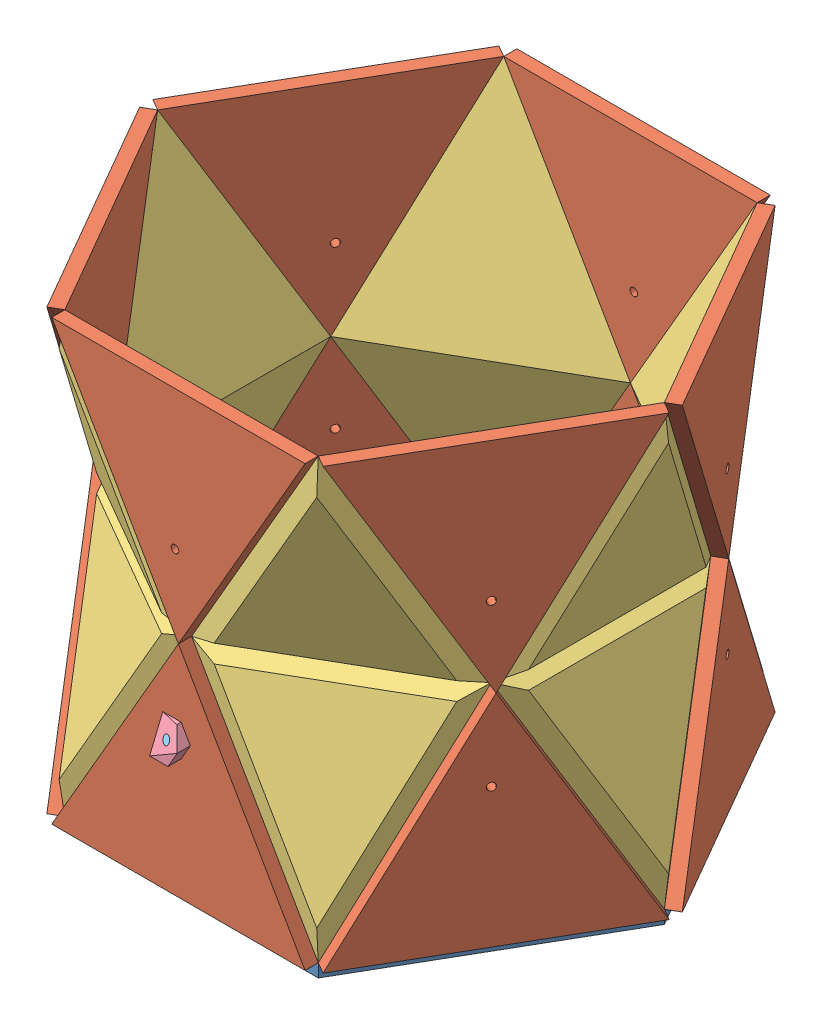
SolidWorks assembly rockPot, configuration Default. Lengths in mm.
Overall size (131.34 103 125.83).
31 component instances, 6 part files, 3 mates.
Components (placement in the parent):
- base^rockPot-2: base^rockPot [Default] at origin size (115.47 3 100) (virtual)
- ring^rockPot-2: ring^rockPot [Default] at origin size (131.34 50 125.83) (virtual)
  - template^ring_rockPot-1: template^ring_rockPot [Default] at (0 3 0) x (1 0 0) z (0 1 0) size (115.47 100 0) (virtual)
  - triA^ring_rockPot-1: triA^ring_rockPot [Default] at (0 0 50) size (57.74 50 3) (virtual)
  - triB^ring_rockPot-1: triB^ring_rockPot [Default] at origin size (43.3 50 25.83) (virtual)
  - triA^ring_rockPot-2: triA^ring_rockPot [Default] at (43.3013 0 25) x (0.5 0 -0.866025) z (0.866025 0 0.5) size (57.74 50 3) (virtual)
  - triA^ring_rockPot-3: triA^ring_rockPot [Default] at (43.3013 0 -25) x (-0.5 0 -0.866025) z (0.866025 0 -0.5) size (57.74 50 3) (virtual)
  - triA^ring_rockPot-4: triA^ring_rockPot [Default] at (0 0 -50) x (-1 0 0) z (0 0 -1) size (57.74 50 3) (virtual)
  - triA^ring_rockPot-5: triA^ring_rockPot [Default] at (-43.3013 0 -25) x (-0.5 0 0.866025) z (-0.866025 0 -0.5) size (57.74 50 3) (virtual)
  - triA^ring_rockPot-6: triA^ring_rockPot [Default] at (-43.3013 0 25) x (0.5 0 0.866025) z (-0.866025 0 0.5) size (57.74 50 3) (virtual)
  - triB^ring_rockPot-2: triB^ring_rockPot [Default] x (0.5 0 -0.866025) z (0.866025 0 0.5) size (43.3 50 25.83) (virtual)
  - triB^ring_rockPot-3: triB^ring_rockPot [Default] x (-0.5 0 -0.866025) z (0.866025 0 -0.5) size (43.3 50 25.83) (virtual)
  - triB^ring_rockPot-4: triB^ring_rockPot [Default] x (-1 0 0) z (0 0 -1) size (43.3 50 25.83) (virtual)
  - triB^ring_rockPot-5: triB^ring_rockPot [Default] x (-0.5 0 0.866025) z (-0.866025 0 -0.5) size (43.3 50 25.83) (virtual)
  - triB^ring_rockPot-6: triB^ring_rockPot [Default] x (0.5 0 0.866025) z (-0.866025 0 0.5) size (43.3 50 25.83) (virtual)
- ring^rockPot-8: ring^rockPot [MirrorDefault] at (0 106 0) x (1 0 0) z (0 0 -1) size (131.34 50 125.83) (virtual)
  - template^ring_rockPot-1: template^ring_rockPot [Default] at (0 3 0) x (1 0 0) z (0 -1 0) size (115.47 100 0) (virtual)
  - triA^ring_rockPot-1: triA^ring_rockPot [MirrorDefault] at (0 0 -50) size (57.74 50 3) (virtual)
  - triB^ring_rockPot-1: triB^ring_rockPot [MirrorDefault] at origin size (43.3 50 25.83) (virtual)
  - triA^ring_rockPot-2: triA^ring_rockPot [MirrorDefault] at (-43.3013 0 -25) x (0.5 0 -0.866025) z (0.866025 0 0.5) size (57.74 50 3) (virtual)
  - triA^ring_rockPot-3: triA^ring_rockPot [MirrorDefault] at (-43.3013 0 25) x (-0.5 0 -0.866025) z (0.866025 0 -0.5) size (57.74 50 3) (virtual)
  - triA^ring_rockPot-4: triA^ring_rockPot [MirrorDefault] at (0 0 50) x (-1 0 0) z (0 0 -1) size (57.74 50 3) (virtual)
  - triA^ring_rockPot-5: triA^ring_rockPot [MirrorDefault] at (43.3013 0 25) x (-0.5 0 0.866025) z (-0.866025 0 -0.5) size (57.74 50 3) (virtual)
  - triA^ring_rockPot-6: triA^ring_rockPot [MirrorDefault] at (43.3013 0 -25) x (0.5 0 0.866025) z (-0.866025 0 0.5) size (57.74 50 3) (virtual)
  - triB^ring_rockPot-2: triB^ring_rockPot [MirrorDefault] x (0.5 0 0.866025) z (-0.866025 0 0.5) size (43.3 50 25.83) (virtual)
  - triB^ring_rockPot-3: triB^ring_rockPot [MirrorDefault] x (-0.5 0 0.866025) z (-0.866025 0 -0.5) size (43.3 50 25.83) (virtual)
  - triB^ring_rockPot-4: triB^ring_rockPot [MirrorDefault] x (-1 0 0) z (0 0 -1) size (43.3 50 25.83) (virtual)
  - triB^ring_rockPot-5: triB^ring_rockPot [MirrorDefault] x (-0.5 0 -0.866025) z (0.866025 0 -0.5) size (43.3 50 25.83) (virtual)
  - triB^ring_rockPot-6: triB^ring_rockPot [MirrorDefault] x (0.5 0 -0.866025) z (0.866025 0 0.5) size (43.3 50 25.83) (virtual)
- hold^rockPot-1: hold^rockPot [Default] at (9.5373 -1.4133 53) size (6.28 7.25 3) (virtual)
- filamentBolt^rockPot-1: filamentBolt^rockPot [Default] at origin size (2.1 1.95 6.84) (virtual)
Mates (geometry in assembly coordinates):
- Coincident4: coincident anti-aligned: plane of ring^rockPot-2/triA^ring_rockPot-1 through (0 0 53) normal (0 0 1); plane of hold^rockPot-1 through (9.5373 -1.4133 53) normal (0 0 -1)
- Coincident6: coincident: unknown of hold^rockPot-1
- Parallel1: parallel aligned: plane of ring^rockPot-2/triA^ring_rockPot-1 through (-28.8675 3 53) normal (0 -1 0); plane of hold^rockPot-1 through (-3.5589 30.6145 56) normal (0 -1 0)
